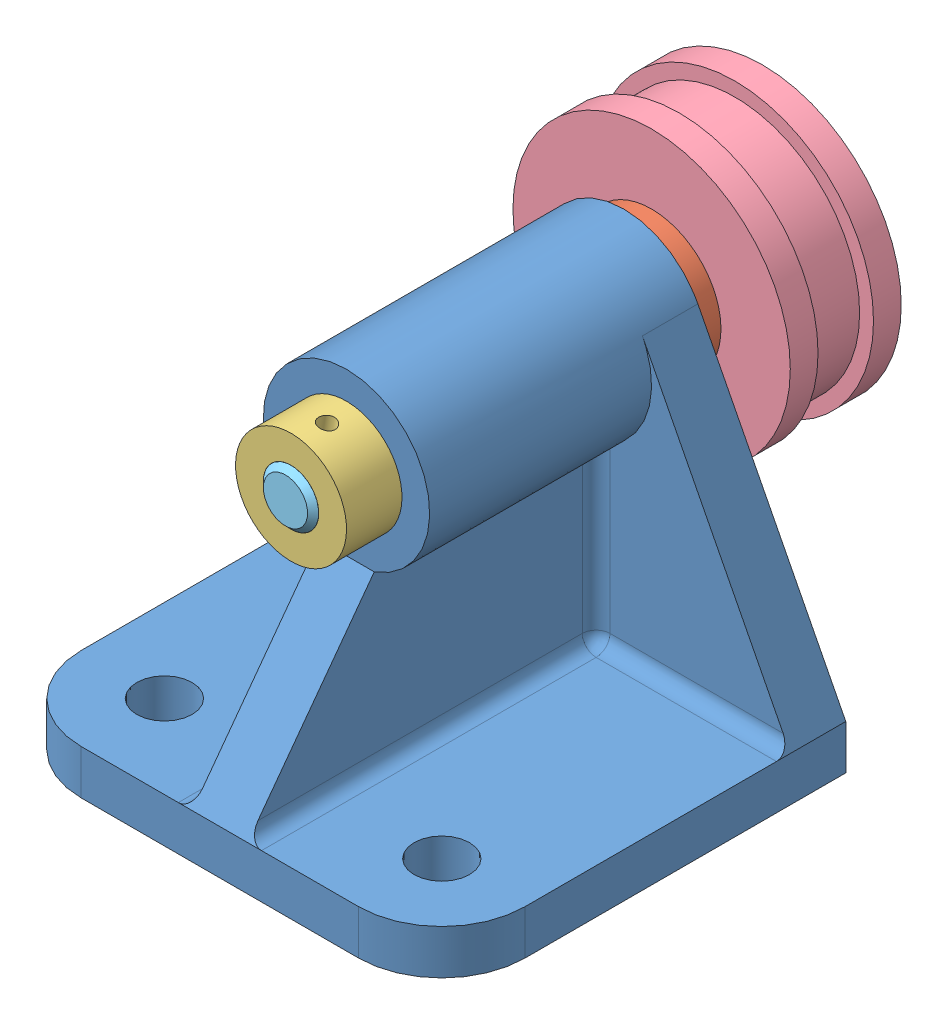
SolidWorks assembly Assem1, configuration Default. Lengths in mm.
Overall size (160 156.06 215.64).
5 component instances, 5 part files, 8 mates.
Components (placement in the parent):
- Part1-1: Part1 [Default] at (10.7779 23.8063 148.4314) size (160 136.06 145.64)
- Part2-1: Part2 [Default] at (10.7779 121.8369 65.6135) x (0.87316 -0.487434 0) z (0 0 1) size (50 50 10)
- Part3-1: Part3 [Default] at (10.7779 121.8369 175.6135) x (0.988739 -0.149648 0) z (0 0 1) size (40 40 20)
- Part4-1: Part4 [Default] at (10.7779 121.8369 65.6135) x (1 0 0) z (0 0 -1) size (100 100 40)
- Part5-1: Part5 [Default] at (10.7779 121.8369 5.6135) x (-0.988739 0.149648 0) z (0 0 1) size (40 40 192)
Mates (geometry in assembly coordinates):
- Concentric1: concentric anti-aligned: cylinder of Part4-1 through (10.7779 121.8369 25.6135) axis (0 0 1) radius 15; cylinder of Part5-1 through (10.7779 121.8369 75.6135) axis (0 0 -1) radius 15
- Concentric2: concentric aligned: cylinder of Part3-1 through (10.7779 121.8369 195.6135) axis (0 0 -1) radius 10; cylinder of Part5-1 through (10.7779 121.8369 75.6135) axis (0 0 -1) radius 15
- Concentric3: concentric aligned: cylinder of Part1-1 through (10.7779 121.8369 175.6135) axis (0 0 -1) radius 10; cylinder of Part5-1 through (10.7779 121.8369 75.6135) axis (0 0 -1) radius 15
- Coincident3: coincident anti-aligned: plane of Part1-1 through (90.7779 31.8369 75.6135) normal (0 0 -1); plane of Part5-1 through (10.7779 121.8369 75.6135) normal (0 0 1)
- Concentric4: concentric anti-aligned: cylinder of Part3-1 through (6.5878 94.1522 185.6135) axis (0.149648 0.988739 0) radius 3; cylinder of Part5-1 through (14.0702 143.5891 185.6135) axis (-0.149648 -0.988739 0) radius 3
- Concentric5: concentric aligned: cylinder of Part2-1 through (10.7779 121.8369 75.6135) axis (0 0 -1) radius 15; cylinder of Part5-1 through (10.7779 121.8369 75.6135) axis (0 0 -1) radius 15
- Coincident4: coincident anti-aligned: plane of Part2-1 through (10.7779 121.8369 65.6135) normal (0 0 -1); plane of Part4-1 through (10.7779 121.8369 65.6135) normal (0 0 1)
- Coincident5: coincident anti-aligned: plane of Part4-1 through (10.7779 121.8369 25.6135) normal (0 0 -1); circle of Part5-1
